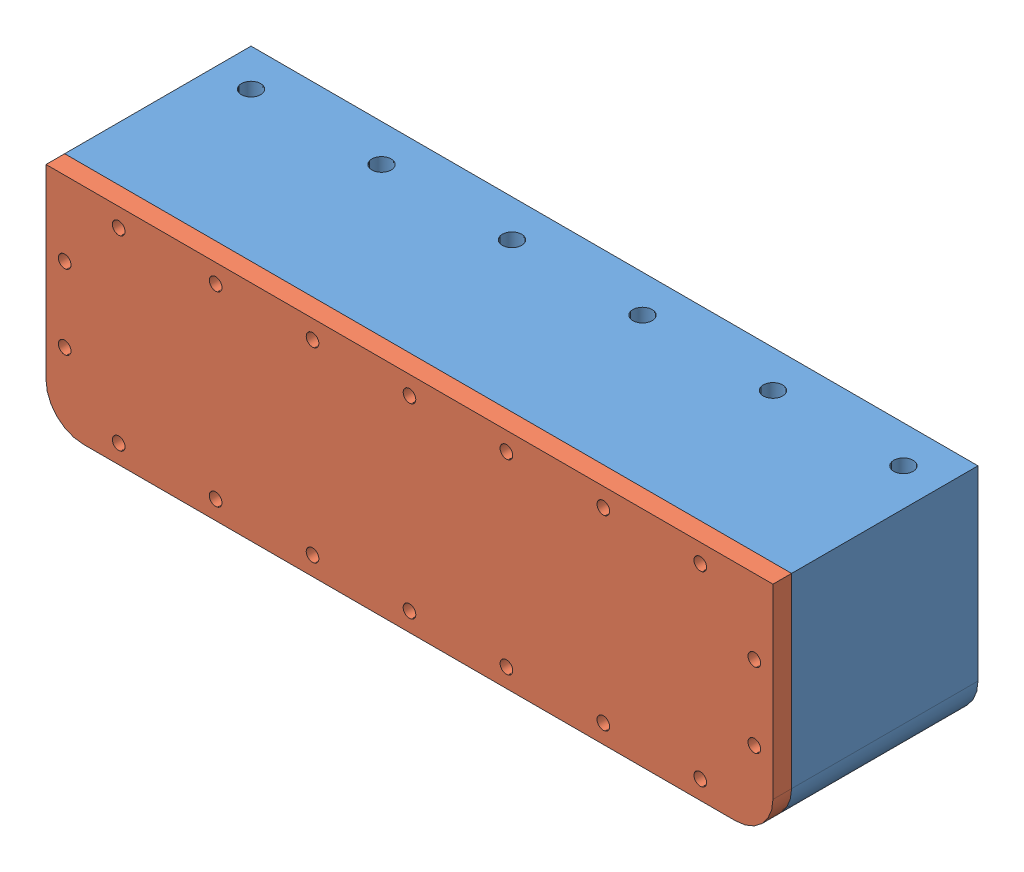
SolidWorks assembly ZED2EnclosureAssembly, configuration Default. Lengths in mm.
Overall size (247.65 76.2 69.85).
3 component instances, 3 part files, 5 mates.
Components (placement in the parent):
- ZED2Enclosure-1: ZED2Enclosure [Default] at origin size (247.65 76.2 63.5)
- ZED2EnclosureFront-1: ZED2EnclosureFront [Default] at (0 38.1 31.75) size (247.65 76.2 6.35)
- ZED2.step-1: ZED2.step [Default] at (-0.3678 -4.5732 0.15) x (-1 0 0) z (0 1 0) size (174.74 41.61 29.73)
Mates (geometry in assembly coordinates):
- Coincident3: coordinate: point of ZED2Enclosure-1
- Coincident4: coincident anti-aligned: plane of ZED2Enclosure-1 through (-123.825 76.2 31.75) normal (0 0 1); plane of ZED2EnclosureFront-1 through (0 38.1 31.75) normal (0 0 -1)
- Coincident5: coincident aligned: plane of ZED2Enclosure-1 through (-123.825 76.2 -31.75) normal (-1 0 0); plane of ZED2EnclosureFront-1 through (-123.825 76.2 38.1) normal (-1 0 0)
- Coincident6: coincident aligned: plane of ZED2Enclosure-1 through (0 76.2 0) normal (0 1 0); plane of ZED2EnclosureFront-1 through (-123.825 76.2 38.1) normal (0 1 0)
- Coincident7: coincident anti-aligned: plane of ZED2EnclosureFront-1 through (0 38.1 31.75) normal (0 0 -1); plane of ZED2.step-1 through (-0.3678 37.7977 31.75) normal (0 0 1)
